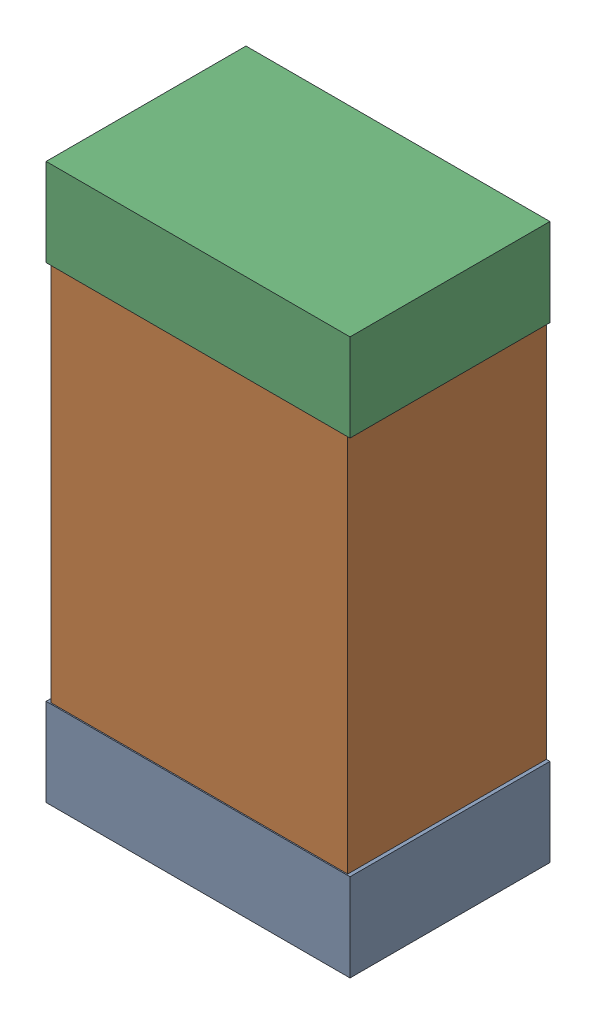
SolidWorks assembly C2Kanaloa_v2.0.0_Motor, configuration Default. Lengths in mm.
Overall size (1.3 2.38 0.85).
6 component instances, 2 part files, 0 mates.
Components (placement in the parent):
- 330415056-1: 330415056 [Default] at (83.312 119.65 0) size (1.3 0.38 0.85)
  - Extruded_2-1: Extruded_2 [Default] at origin size (1.3 0.38 0.85)
- 334787376-1: 334787376 [Default] at (83.312 120.65 0) size (1.27 2.2 0.85)
  - Extruded_16-1: Extruded_16 [Default] at origin size (1.27 2.2 0.85)
- 330415056-2: 330415056 [Default] at (83.312 121.65 0) size (1.3 0.38 0.85)
  - Extruded_2-1: Extruded_2 [Default] at origin size (1.3 0.38 0.85)
